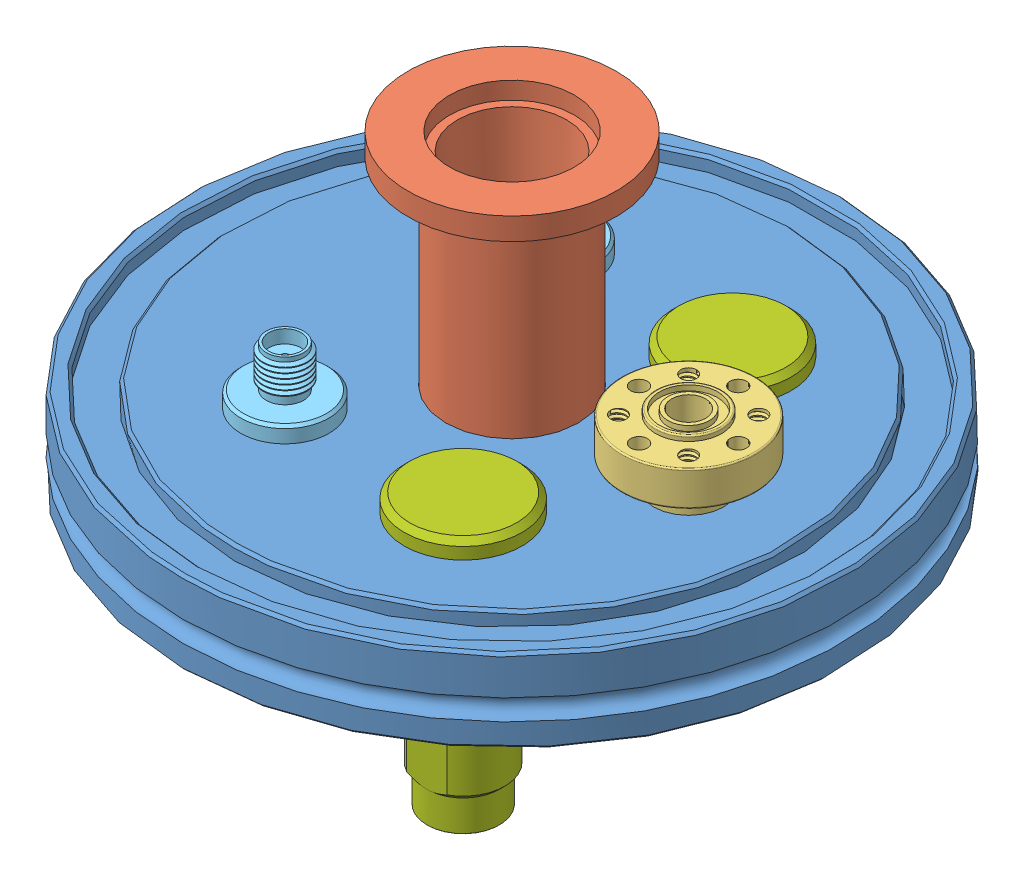
SolidWorks assembly LPC_TopFlange, configuration Default. Lengths in mm.
Overall size (95 68.16 95).
13 component instances, 8 part files, 34 mates.
Components (placement in the parent):
- TopFlange_ISO63B-1: TopFlange_ISO63B [Default] at origin size (95 12 95)
- SamplePort_KF16-machined-1: SamplePort_KF16-machined [Default] at (0 41.4906 -0.2) x (0 0 1) z (0 -1 0) size (30 30 43.66)
- UG387_WaveguideHolder-1: UG387_WaveguideHolder [Default] at (25.45 16 0) x (1 0 0) z (0 1 0) size (19.2 19.2 21.76)
- SMA coax connector-1: SMA coax connector [Default] at (-13.479 -9.4863 -19.2501) x (0 0 1) z (0 -1 0) size (9.15 7.92 20.29)
- SMA Female to Female Bulkhead Hermetic Adapter Body-1: SMA Female to Female Bulkhead Hermetic Adapter Body [Default] at (-13.479 14.286 -19.2501) x (0 0 1) z (0 -1 0) size (12.7 12.7 22.21)
- SMA Female to Female Bulkhead Hermetic Adapter Nut-1: SMA Female to Female Bulkhead Hermetic Adapter Nut [Default] at (-13.479 8 -19.2501) x (0 0 1) z (0 -1 0) size (11 9.53 1.61)
- SMA coax connector-3: SMA coax connector [Default] at (-13.479 -9.4863 19.2501) x (-0.382669 0 -0.923885) z (0 -1 0) size (9.15 7.92 20.29)
- SMA Female to Female Bulkhead Hermetic Adapter Body-3: SMA Female to Female Bulkhead Hermetic Adapter Body [Default] at (-13.479 14.286 19.2501) x (0 0 -1) z (0 -1 0) size (12.7 12.7 22.21)
- SMA Female to Female Bulkhead Hermetic Adapter Nut-3: SMA Female to Female Bulkhead Hermetic Adapter Nut [Default] at (-13.479 6.4125 19.2501) x (-1 0 0) z (0 1 0) size (11 9.53 1.61)
- LEMO_Body_SWH.1S.306.CLLPV-1: LEMO_Body_SWH.1S.306.CLLPV [Default] at (12.3579 -24.5 -19.398) x (0 0 1) z (0 1 0) size (17 17 39)
- LEMO_Nut_SWH.1S.306.CLLPV-1: LEMO_Nut_SWH.1S.306.CLLPV [Default] at (12.3579 -8.5 19.398) x (-0.837169 0 -0.546944) z (0 1 0) size (14 15.8 2.5)
- LEMO_Body_SWH.1S.306.CLLPV-3: LEMO_Body_SWH.1S.306.CLLPV [Default] at (12.3579 -24.5 19.398) x (0 0 -1) z (0 1 0) size (17 17 39)
- LEMO_Nut_SWH.1S.306.CLLPV-3: LEMO_Nut_SWH.1S.306.CLLPV [Default] at (12.3579 -8.5 -19.398) x (0.59748 0 0.801884) z (0 1 0) size (14 15.8 2.5)
Mates (geometry in assembly coordinates):
- Concentric1: concentric anti-aligned: circle of TopFlange_ISO63B-1; circle of UG387_WaveguideHolder-1
- Coincident1: coincident aligned: plane of TopFlange_ISO63B-1 through (31.1 0 0) normal (0 -1 0); plane of UG387_WaveguideHolder-1 through (25.45 0 0) normal (0 -1 0)
- Coincident2: coincident aligned: plane of TopFlange_ISO63B-1 through (31.1 0 0) normal (0 -1 0); plane of SamplePort_KF16-machined-1 through (0 0 9.5) normal (0 -1 0)
- Concentric2: concentric aligned: circle of TopFlange_ISO63B-1; circle of SamplePort_KF16-machined-1
- Coincident3: coincident anti-aligned: plane of TopFlange_ISO63B-1 through (0 12 0) normal (0 1 0); plane of SMA Female to Female Bulkhead Hermetic Adapter Body-1 through (-13.479 12 -19.2501) normal (0 -1 0)
- Parallel1: parallel aligned: plane of TopFlange_ISO63B-1 through (-10.9932 0 -22.4093) normal (0 0 1); plane of SMA Female to Female Bulkhead Hermetic Adapter Body-1 through (-16.654 18.3994 -15.7258) normal (0 0 1)
- Concentric3: concentric aligned: circle of TopFlange_ISO63B-1; circle of SMA Female to Female Bulkhead Hermetic Adapter Body-1
- Coincident5: coincident anti-aligned: plane of SMA coax connector-1 through (-13.479 -1.9679 -19.2501) normal (0 1 0); plane of SMA Female to Female Bulkhead Hermetic Adapter Body-1 through (-13.479 -1.9679 -19.2501) normal (0 -1 0)
- Concentric4: concentric aligned: circle of SMA coax connector-1; circle of SMA Female to Female Bulkhead Hermetic Adapter Body-1
- Concentric5: concentric anti-aligned: circle of SMA Female to Female Bulkhead Hermetic Adapter Body-1; circle of SMA Female to Female Bulkhead Hermetic Adapter Nut-1
- Coincident6: coincident anti-aligned: plane of TopFlange_ISO63B-1 through (-13.479 8 -19.2501) normal (0 -1 0); plane of SMA Female to Female Bulkhead Hermetic Adapter Nut-1 through (-18.2415 8 -11.0012) normal (0 1 0)
- Concentric7: concentric aligned: circle of SMA Female to Female Bulkhead Hermetic Adapter Body-2; circle of SMA coax connector-2
- Coincident7: coincident anti-aligned: plane of SMA Female to Female Bulkhead Hermetic Adapter Body-2 through (-13.7085 -1.9679 -19.5777) normal (0 -1 0); plane of SMA coax connector-2 through (-13.7085 -1.9679 -19.5777) normal (0 1 0)
- Concentric8: concentric anti-aligned: circle of TopFlange_ISO63B-1; circle of SMA Female to Female Bulkhead Hermetic Adapter Body-3
- Parallel2: parallel aligned: plane of TopFlange_ISO63B-1 through (9.4403 0 24.698) normal (0 0 -1); plane of SMA Female to Female Bulkhead Hermetic Adapter Body-3 through (-10.304 18.3994 15.7258) normal (0 0 -1)
- Coincident9: coincident anti-aligned: plane of TopFlange_ISO63B-1 through (0 12 0) normal (0 1 0); plane of SMA Female to Female Bulkhead Hermetic Adapter Body-3 through (-13.479 12 19.2501) normal (0 -1 0)
- Concentric10: concentric aligned: circle of TopFlange_ISO63B-1; circle of SMA Female to Female Bulkhead Hermetic Adapter Nut-3
- Coincident10: coincident anti-aligned: plane of TopFlange_ISO63B-1 through (-13.479 8 19.2501) normal (0 -1 0); plane of SMA Female to Female Bulkhead Hermetic Adapter Nut-3 through (-21.7279 8 24.0126) normal (0 1 0)
- Coincident11: coincident anti-aligned: plane of SMA coax connector-3 through (-13.479 -1.9679 19.2501) normal (0 1 0); plane of SMA Female to Female Bulkhead Hermetic Adapter Body-3 through (-13.479 -1.9679 19.2501) normal (0 -1 0)
- Concentric12: concentric aligned: circle of SMA coax connector-3; circle of SMA Female to Female Bulkhead Hermetic Adapter Body-3
- Parallel3: parallel aligned: plane of TopFlange_ISO63B-1 through (9.4403 0 -14.098) normal (0 0 -1); plane of LEMO_Body_SWH.1S.306.CLLPV-1 through (15.2626 -20 -24.648) normal (0 0 -1)
- Coincident14: coincident anti-aligned: plane of TopFlange_ISO63B-1 through (0 12 0) normal (0 1 0); plane of LEMO_Body_SWH.1S.306.CLLPV-1 through (12.3579 12 -19.398) normal (0 -1 0)
- Parallel4: parallel anti-aligned: plane of TopFlange_ISO63B-1 through (9.4403 0 14.098) normal (0 0 1); plane of LEMO_Body_SWH.1S.306.CLLPV-3 through (15.2626 -20 14.148) normal (0 0 -1)
- Coincident17: coincident anti-aligned: plane of TopFlange_ISO63B-1 through (0 12 0) normal (0 1 0); plane of LEMO_Body_SWH.1S.306.CLLPV-3 through (12.3579 12 19.398) normal (0 -1 0)
- Parallel5: parallel anti-aligned: plane of TopFlange_ISO63B-1 through (9.4403 0 -14.098) normal (0 0 -1); plane of LEMO_Body_SWH.1S.306.CLLPV-1 through (9.4532 -20 -14.148) normal (0 0 1)
- Coincident19: coincident anti-aligned: plane of TopFlange_ISO63B-1 through (0 12 0) normal (0 1 0); plane of LEMO_Body_SWH.1S.306.CLLPV-1 through (12.3579 12 -19.398) normal (0 -1 0)
- Concentric14: concentric aligned: circle of TopFlange_ISO63B-1; circle of LEMO_Body_SWH.1S.306.CLLPV-1
- Concentric15: concentric aligned: circle of LEMO_Body_SWH.1S.306.CLLPV-1; circle of LEMO_Nut_SWH.1S.306.CLLPV-3
- Coincident20: coincident anti-aligned: plane of TopFlange_ISO63B-1 through (31.1 0 0) normal (0 -1 0); plane of LEMO_Nut_SWH.1S.306.CLLPV-3 through (12.3579 0 -19.398) normal (0 1 0)
- Coincident21: coincident anti-aligned: plane of TopFlange_ISO63B-1 through (31.1 0 0) normal (0 -1 0); plane of LEMO_Nut_SWH.1S.306.CLLPV-1 through (12.3579 0 19.398) normal (0 1 0)
- Parallel6: parallel aligned: plane of TopFlange_ISO63B-1 through (9.4403 0 24.698) normal (0 0 -1); plane of LEMO_Body_SWH.1S.306.CLLPV-3 through (15.2626 -20 14.148) normal (0 0 -1)
- Coincident23: coincident anti-aligned: plane of TopFlange_ISO63B-1 through (0 12 0) normal (0 1 0); plane of LEMO_Body_SWH.1S.306.CLLPV-3 through (12.3579 12 19.398) normal (0 -1 0)
- Concentric17: concentric aligned: circle of TopFlange_ISO63B-1; circle of LEMO_Body_SWH.1S.306.CLLPV-3
- Concentric18: concentric anti-aligned: circle of LEMO_Nut_SWH.1S.306.CLLPV-1; circle of LEMO_Body_SWH.1S.306.CLLPV-3
